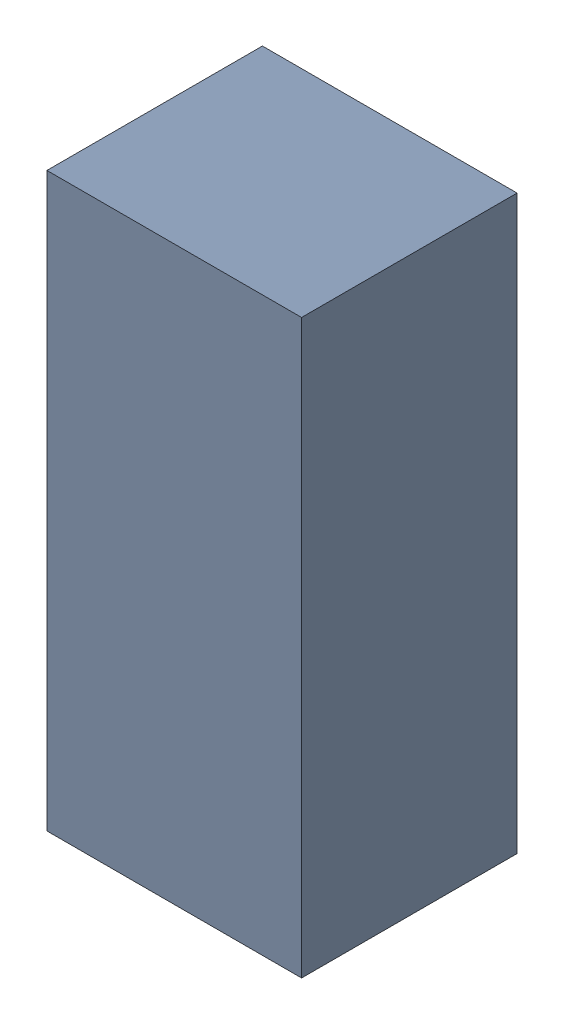
SolidWorks assembly D2, configuration Default. Lengths in mm.
Overall size (1.3 2.92 1.1).
2 component instances, 1 part files, 0 mates.
Components (placement in the parent):
- 6151663024-1: 6151663024 [Default] at (20.336 -5.903 0.01) size (1.3 2.92 1.1)
  - Extruded-1: Extruded [Default] at origin size (1.3 2.92 1.1)
